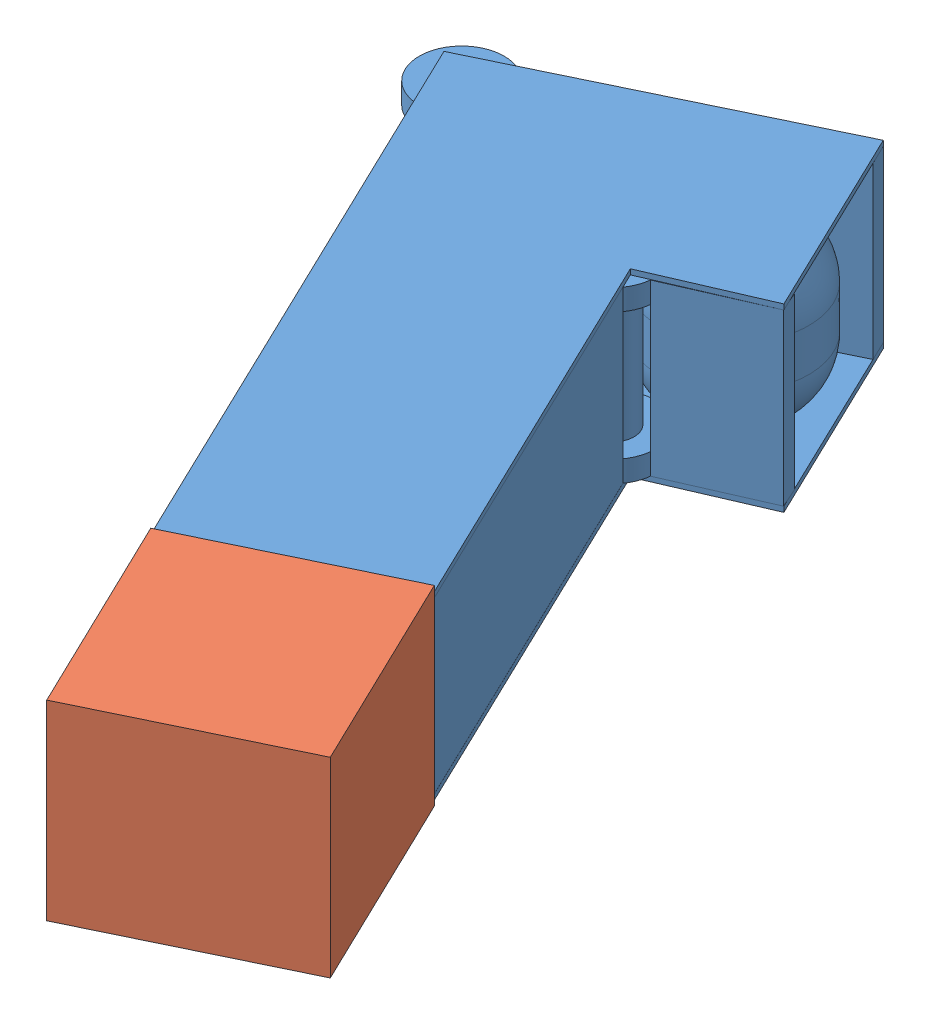
SolidWorks assembly FRC2020_Shooter_and_Indexer_v1, configuration Default. Lengths in mm.
Overall size (685.67 228.6 1120.68).
2 component instances, 2 part files, 3 mates.
Components (placement in the parent):
- BALL ELEVATOR-1: BALL ELEVATOR [Default] at (414.1171 710.2659 489.0889) size (615.5 215.9 902.25)
- FRC2020_Shooter_volume_v1-1: FRC2020_Shooter_volume_v1 [Default] at (493.9192 770.7179 1430.21) x (0 -1 0) z (-0.900782 0 0.434272) size (228.6 266.7 254)
Mates (geometry in assembly coordinates):
- Coincident1: coincident anti-aligned: plane of BALL ELEVATOR-1 through (313.6262 913.4659 1517.1304) normal (0.434272 0 0.900782); plane of FRC2020_Shooter_volume_v1-1 through (493.9192 770.7179 1430.21) normal (-0.434272 0 -0.900782)
- Distance2: distance = 6.35 mm aligned: plane of BALL ELEVATOR-1 through (254.0056 703.9159 1099.602) normal (0 -1 0); plane of FRC2020_Shooter_volume_v1-1 through (646.805 697.5659 1652.579) normal (0 -1 0)
- Distance1: distance = 0 mm: line of BALL ELEVATOR-1 through (302.1861 913.4659 1522.6458) axis (0 -1 0); line of FRC2020_Shooter_volume_v1-1 through (302.1861 926.1659 1522.6458) axis (0 -1 0)
